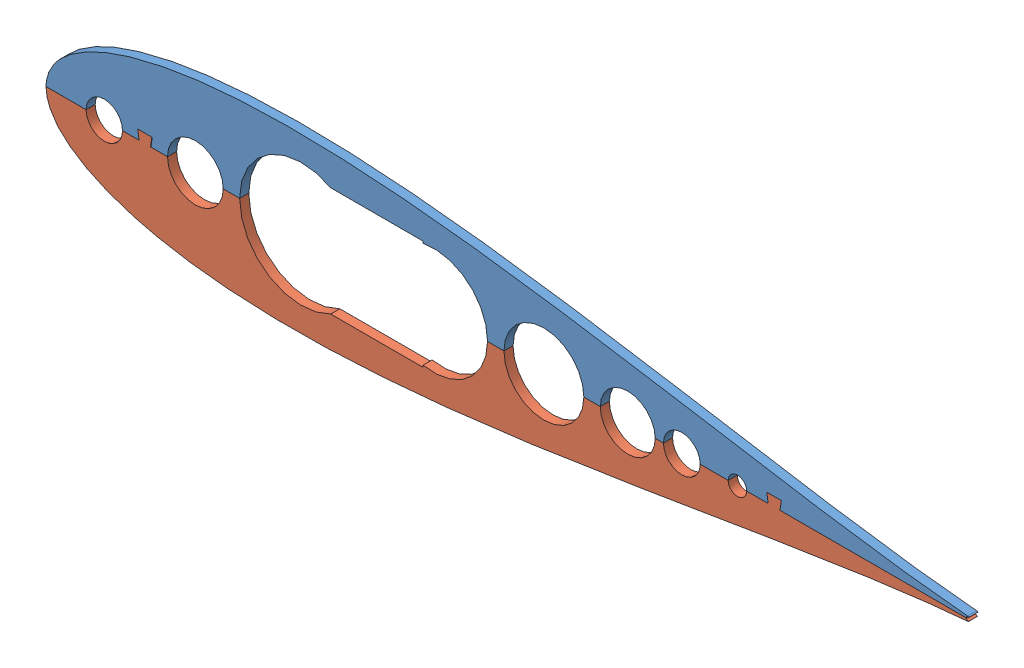
SolidWorks assembly Full Scale. Assembly Airfoil Servo Access, configuration Default. Lengths in mm.
Overall size (643.44 120.78 6.35).
2 component instances, 2 part files, 3 mates.
Components (placement in the parent):
- Prototype rib mk 4 female-1: Prototype rib mk 4 female [Default] at (-578.6111 14.9076 101.6027) size (643.6 60.39 6.35)
- Prototype rib mk 4 male-1: Prototype rib mk 4 male [Default] at (-578.6111 14.9076 101.6027) size (643.6 66.74 6.35)
Mates (geometry in assembly coordinates):
- Coincident7: coincident aligned: plane of Prototype rib mk 4 female-1 through (-578.6111 14.9076 107.9527) normal (0 0 1); plane of Prototype rib mk 4 male-1 through (-578.6111 14.9076 107.9527) normal (0 0 1)
- Concentric1: concentric aligned: circle of Prototype rib mk 4 female-1; circle of Prototype rib mk 4 male-1
- Coincident9: coincident aligned: line of Prototype rib mk 4 female-1 through (-578.6111 14.9076 107.9527) axis (1 0 0); line of Prototype rib mk 4 male-1 through (-578.6111 14.9076 107.9527) axis (1 0 0)
